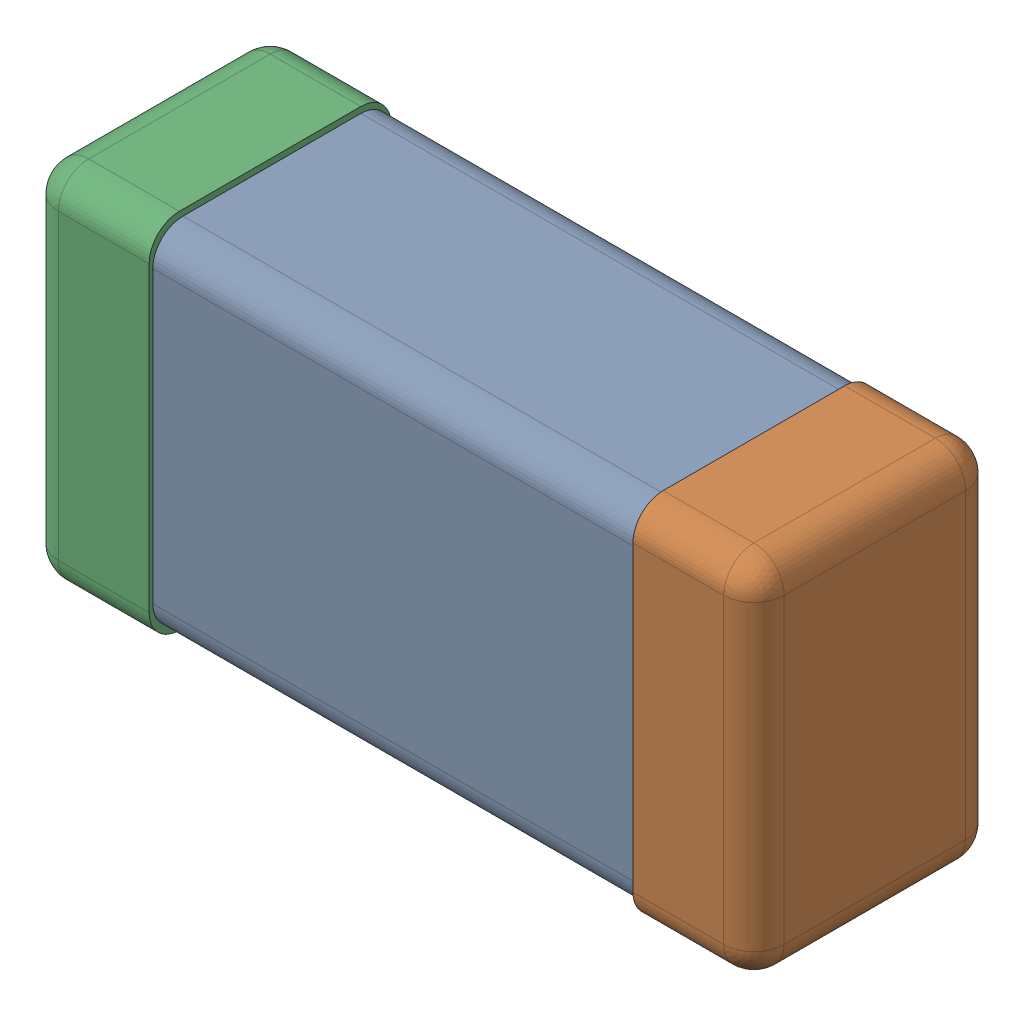
SolidWorks assembly C0201_020_17, configuration Standard. Lengths in mm.
Overall size (0.6 0.3 0.2).
3 component instances, 3 part files, 0 mates.
Components (placement in the parent):
- Part 3_2-1: Part 3_2 [Standard] at (0 0 -7.3015) size (0.5 0.29 0.2)
- Part 2_2-1: Part 2_2 [Standard] at (0 0 -7.3) size (0.1 0.3 0.2)
- Part 1_2-1: Part 1_2 [Standard] at (0 0 -7.3) size (0.1 0.3 0.2)
